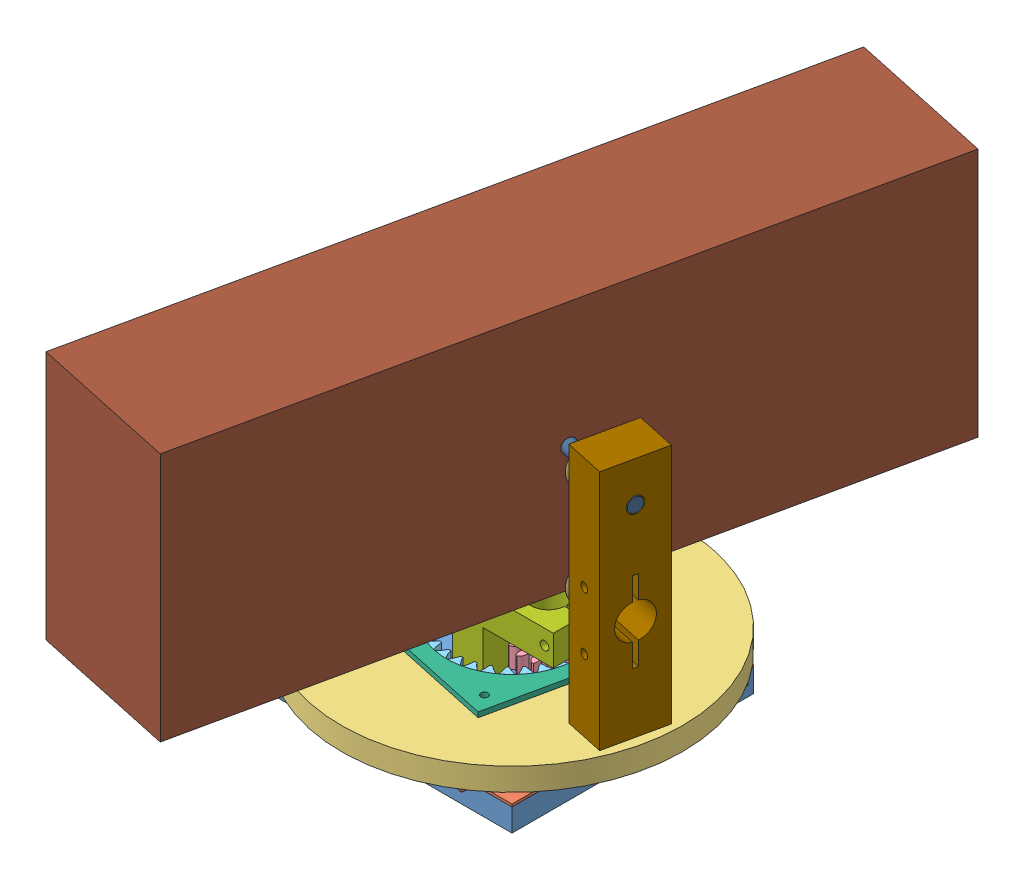
SolidWorks assembly TermProjectCAD, configuration Default. Lengths in mm.
Overall size (256.06 242.25 444.39).
17 component instances, 14 part files, 32 mates.
Components (placement in the parent):
- Bottom Wooden Base^TermProjectCAD-1: Bottom Wooden Base^TermProjectCAD [Default] at origin size (152.4 14.29 152.4) (virtual)
- Turn Table Half^TermProjectCAD-1: Turn Table Half^TermProjectCAD [Default] at origin size (152.4 3.97 152.4) (virtual)
- Turn Table Half^TermProjectCAD-2: Turn Table Half^TermProjectCAD [Default] at (0 36.5125 0) x (0.977603 0 0.210459) z (0.210459 0 -0.977603) size (152.4 3.97 152.4) (virtual)
- Top Wooden Base^TermProjectCAD-1: Top Wooden Base^TermProjectCAD [Default] at (0 15.875 0) x (-0.977603 0 -0.210459) z (0.210459 0 -0.977603) size (215.53 14.29 215.53) (virtual)
- spur gear_ai-1: spur gear_ai [Inch - Spur gear 10DP 12T 20PA 0.5FW ---S12N3.0H2.0L0.25N] at (22.86 39.6875 0) x (0 -1 0) z (-0.120388 0 -0.992727) size (12.7 34.56 34.56)
- internal spur gear_ai-3: internal spur gear_ai [Inch - Internal spur gear 10DP 30T 20PA 0.5FW ---S30S1.0OD 1.0AF] at (0 39.6875 0) x (0 -1 0) z (0.977603 0 0.210459) size (12.7 82.6 82.6)
- Internal Gear Inlay^TermProjectCAD-2: Internal Gear Inlay^TermProjectCAD [Default] at (0 26.9875 0) x (0.210459 0 -0.977603) z (0.977603 0 0.210459) size (101.6 12.7 101.6) (virtual)
- Motor Mount 1^TermProjectCAD-1: Motor Mount 1^TermProjectCAD [Default] at (0.635 14.2875 0) x (0 0 -1) z (1 0 0) size (38.1 50.8 63.5) (virtual)
- instrument ball bearing_ai-1: instrument ball bearing_ai [AFBMA 12.2 - 0.2500 - 0.7500 - 0.2188 - 8,SI,NC,8] at (78.62 163.5125 16.9254) x (0.977603 0 0.210459) z (-0.081114 0.922743 0.376783) size (5.56 19.05 19.05)
- instrument ball bearing_ai-2: instrument ball bearing_ai [AFBMA 12.2 - 0.2500 - 0.7500 - 0.2188 - 8,SI,NC,8] at (-78.62 163.5125 -16.9254) x (-0.977603 0 -0.210459) z (0.055667 -0.964385 -0.258579) size (5.56 19.05 19.05)
- Wood Obelisks^TermProjectCAD-1: Wood Obelisks^TermProjectCAD [Default] at (0 36.5125 0) x (0.977603 0 0.210459) z (-0.210459 0 0.977603) size (203.2 152.4 38.1) (virtual)
- shaft^TermProjectCAD-1: shaft^TermProjectCAD [Default] at (0 163.5125 0) x (0.977603 0 0.210459) z (-0.210459 0 0.977603) size (203.2 8.73 8.73) (virtual)
- nerf gun^TermProjectCAD-1: nerf gun^TermProjectCAD [Default] at (0 163.5125 0) x (0.210459 0 -0.977603) z (0.977603 0 0.210459) size (434.34 157.48 93.98) (virtual)
- Pulley^TermProjectCAD-1: Pulley^TermProjectCAD [Default] at (65.1817 163.5125 14.0323) x (0.210459 0 -0.977603) z (0.977603 0 0.210459) size (25.4 25.4 6.35) (virtual)
- Pulley^TermProjectCAD-2: Pulley^TermProjectCAD [Default] at (65.1817 100.0125 14.0323) x (0.151221 0.695494 -0.702439) z (-0.977603 0 -0.210459) size (25.4 25.4 6.35) (virtual)
- 3dprint gear^TermProjectCAD-1: 3dprint gear^TermProjectCAD [Default] at origin size (35.32 12.7 35.32) (hidden, virtual)
- 3dprint inlay^TermProjectCAD-1: 3dprint inlay^TermProjectCAD [Default] at origin size (120.71 12.7 120.71) (hidden, virtual)
Mates (geometry in assembly coordinates):
- Coincident1: coincident anti-aligned: plane of Turn Table Half^TermProjectCAD-1 through (0 18.2563 0) normal (0 1 0); plane of Turn Table Half^TermProjectCAD-2 through (0 18.2563 0) normal (0 -1 0)
- Concentric1: concentric anti-aligned: cylinder of Turn Table Half^TermProjectCAD-1 through (0 15.875 0) axis (0 -1 0) radius 59.2667; cylinder of Turn Table Half^TermProjectCAD-2 through (0 20.6375 0) axis (0 1 0) radius 59.2667
- Concentric2: concentric anti-aligned: cylinder of Turn Table Half^TermProjectCAD-2 through (0 20.6375 0) axis (0 1 0) radius 59.2667; cylinder of Top Wooden Base^TermProjectCAD-1 through (0 36.5125 0) axis (0 -1 0) radius 50.8
- Coincident2: coincident anti-aligned: plane of Turn Table Half^TermProjectCAD-2 through (0 22.225 0) normal (0 1 0); plane of Top Wooden Base^TermProjectCAD-1 through (0 22.225 0) normal (0 -1 0)
- Coincident3: coincident anti-aligned: plane of Turn Table Half^TermProjectCAD-2 through (0 36.5125 0) normal (0.977603 0 0.210459); plane of Top Wooden Base^TermProjectCAD-1 through (0 15.875 0) normal (-0.977603 0 -0.210459)
- Concentric3: concentric anti-aligned: cylinder of Top Wooden Base^TermProjectCAD-1 through (0 36.5125 0) axis (0 -1 0) radius 50.8; cylinder of internal spur gear_ai-3 through (0 49.6875 0) axis (0 1 0) radius 41.3017
- Concentric5: concentric aligned: circle of internal spur gear_ai-3; circle of Internal Gear Inlay^TermProjectCAD-2
- Coincident7: coincident aligned: plane of internal spur gear_ai-3 through (-34.7636 39.6875 -7.4839) normal (0 1 0); plane of Internal Gear Inlay^TermProjectCAD-2 through (0 39.6875 0) normal (0 1 0)
- Coincident8: coincident aligned: plane of internal spur gear_ai-3 through (0 39.6875 0) normal (0.210459 0 -0.977603); plane of Internal Gear Inlay^TermProjectCAD-2 through (0 26.9875 0) normal (0.210459 0 -0.977603)
- Coincident9: coincident anti-aligned: plane of Top Wooden Base^TermProjectCAD-1 through (0 36.5125 0) normal (0 1 0); plane of Internal Gear Inlay^TermProjectCAD-2 through (0 36.5125 0) normal (0 -1 0)
- Angle1: planar angle = 0 rad aligned: plane of Internal Gear Inlay^TermProjectCAD-2 through (0 26.9875 0) normal (0.977603 0 0.210459); plane of Turn Table Half^TermProjectCAD-2 through (0 36.5125 0) normal (0.977603 0 0.210459)
- Coincident12: coincident aligned: plane of spur gear_ai-1 through (22.86 39.6875 0) normal (0 1 0); plane of internal spur gear_ai-3 through (-34.7636 39.6875 -7.4839) normal (0 1 0)
- Concentric7: concentric aligned: cylinder of spur gear_ai-1 through (22.86 -11.1126 0) axis (0 1 0) radius 3.175; cylinder of Motor Mount 1^TermProjectCAD-1 through (22.86 46.0375 0) axis (0 1 0) radius 11.1125
- Coincident14: coincident anti-aligned: plane of Bottom Wooden Base^TermProjectCAD-1 through (0 14.2875 0) normal (0 1 0); plane of Motor Mount 1^TermProjectCAD-1 through (0.635 14.2875 0) normal (0 -1 0)
- Coincident15: coincident anti-aligned: plane of Turn Table Half^TermProjectCAD-1 through (0 0 0) normal (0 0 1); plane of Motor Mount 1^TermProjectCAD-1 through (0.635 14.2875 0) normal (0 0 -1)
- GearMate1: gear = 30.48 : 76.2 mm: circle of internal spur gear_ai-3; circle of spur gear_ai-1
- Tangent2: tangent: circle of spur gear_ai-1; circle of internal spur gear_ai-3
- Coincident16: coincident anti-aligned: plane of instrument ball bearing_ai-1 through (83.1074 167.0269 9.2845) normal (0.977603 0 0.210459); plane of Wood Obelisks^TermProjectCAD-1 through (85.3458 188.9125 -1.1132) normal (-0.977603 0 -0.210459)
- Concentric8: concentric aligned: cylinder of instrument ball bearing_ai-1 through (58.4447 163.5125 12.582) axis (0.977603 0 0.210459) radius 9.525; cylinder of Wood Obelisks^TermProjectCAD-1 through (-118.803 163.5125 -25.576) axis (0.977603 0 0.210459) radius 11.075
- Coincident17: coincident anti-aligned: plane of instrument ball bearing_ai-2 through (-79.4858 165.9244 -26.1071) normal (-0.977603 0 -0.210459); plane of Wood Obelisks^TermProjectCAD-1 through (-77.3273 188.9125 -36.1335) normal (0.977603 0 0.210459)
- Concentric9: concentric anti-aligned: cylinder of instrument ball bearing_ai-2 through (-58.4447 163.5125 -12.582) axis (-0.977603 0 -0.210459) radius 9.525; cylinder of Wood Obelisks^TermProjectCAD-1 through (-118.803 163.5125 -25.576) axis (0.977603 0 0.210459) radius 11.075
- Coincident18: coincident anti-aligned: plane of Top Wooden Base^TermProjectCAD-1 through (0 15.875 0) normal (0.210459 0 -0.977603); plane of Wood Obelisks^TermProjectCAD-1 through (0 36.5125 0) normal (-0.210459 0 0.977603)
- Coincident19: coincident anti-aligned: plane of Top Wooden Base^TermProjectCAD-1 through (0 15.875 0) normal (-0.977603 0 -0.210459); plane of Wood Obelisks^TermProjectCAD-1 through (0 36.5125 0) normal (0.977603 0 0.210459)
- Coincident20: coincident anti-aligned: plane of Top Wooden Base^TermProjectCAD-1 through (0 36.5125 0) normal (0 1 0); plane of Wood Obelisks^TermProjectCAD-1 through (0 36.5125 0) normal (0 -1 0)
- Concentric11: concentric aligned: cylinder of instrument ball bearing_ai-2 through (-58.4447 163.5125 -12.582) axis (-0.977603 0 -0.210459) radius 3.175; cylinder of shaft^TermProjectCAD-1 through (99.3244 163.5125 21.3826) axis (-0.977603 0 -0.210459) radius 4.3656
- Coincident21: coincident aligned: plane of Wood Obelisks^TermProjectCAD-1 through (103.3337 188.9125 2.7593) normal (0.977603 0 0.210459); plane of shaft^TermProjectCAD-1 through (99.3244 163.5125 21.3826) normal (0.977603 0 0.210459)
- Concentric12: concentric aligned: cylinder of shaft^TermProjectCAD-1 through (99.3244 163.5125 21.3826) axis (-0.977603 0 -0.210459) radius 4.3656; cylinder of nerf gun^TermProjectCAD-1 through (45.9376 163.5125 9.8895) axis (-0.977603 0 -0.210459) radius 4.3656
- Coincident22: coincident aligned: plane of shaft^TermProjectCAD-1 through (0 163.5125 0) normal (0.977603 0 0.210459); plane of nerf gun^TermProjectCAD-1 through (0 163.5125 0) normal (0.977603 0 0.210459)
- Concentric14: concentric aligned: cylinder of shaft^TermProjectCAD-1 through (99.3244 163.5125 21.3826) axis (-0.977603 0 -0.210459) radius 4.3656; cylinder of Pulley^TermProjectCAD-1 through (68.2855 163.5125 14.7006) axis (-0.977603 0 -0.210459) radius 2.9845
- Coincident23: coincident aligned: plane of Pulley^TermProjectCAD-1 through (62.0778 163.5125 13.3641) normal (-0.977603 0 -0.210459); plane of Pulley^TermProjectCAD-2 through (62.0778 100.0125 13.3641) normal (-0.977603 0 -0.210459)
- Concentric15: concentric anti-aligned: cylinder of Wood Obelisks^TermProjectCAD-1 through (99.3244 100.0125 21.3826) axis (-0.977603 0 -0.210459) radius 11.1125; cylinder of Pulley^TermProjectCAD-2 through (62.0778 100.0125 13.3641) axis (0.977603 0 0.210459) radius 2.9845
- Distance1: distance = 6.35 mm anti-aligned: plane of Pulley^TermProjectCAD-2 through (68.2855 100.0125 14.7006) normal (0.977603 0 0.210459); plane of Wood Obelisks^TermProjectCAD-1 through (78.5026 188.9125 -2.5864) normal (-0.977603 0 -0.210459)
